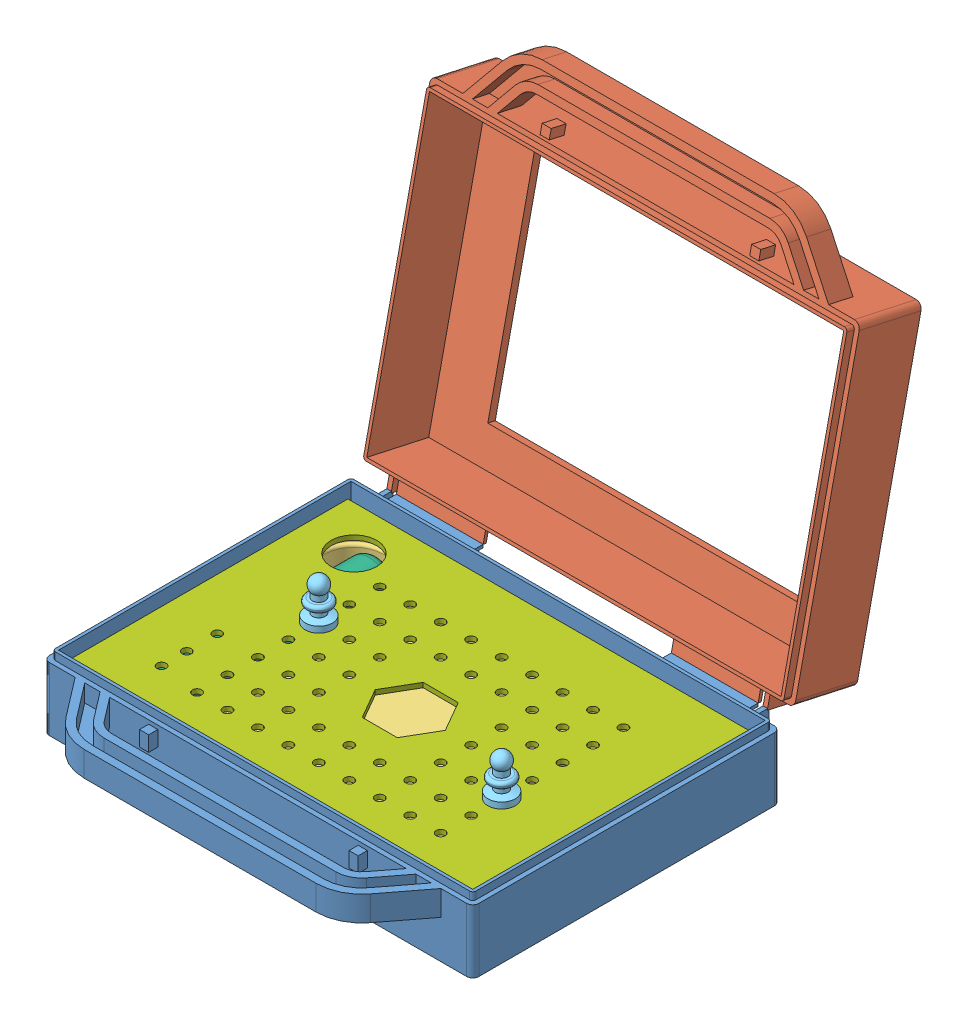
SolidWorks assembly jeu-voyage, configuration Défaut. Lengths in mm.
Overall size (141 142.26 170.67).
8 component instances, 7 part files, 15 mates.
Components (placement in the parent):
- valisette_fond-1: valisette_fond [Défaut] at (-27.5521 -9.989 -62.1133) size (141 23.3 124.3)
- valisette_dessus-1: valisette_dessus [Défaut] at (-27.5521 1.8921 -76.8863) x (-1 0 0) z (0 0.97673 -0.214471) size (141 23.3 124.3)
- support plateau-1: support plateau [Défaut] at (-93.5521 -17.889 36.3867) x (1 0 0) z (0 1 0) size (134 93 15)
- dé-1: dé [Défaut] at (6.4323 -9.889 -21.8934) x (0 1 0) z (0 0 1) size (14 14 14)
- pion-1: pion [Défaut] at (-65.1464 1.9003 -18.5818) x (0.999997 -0.002439 0) z (0 0 1) size (8.97 20.5 8.97)
- sablier(1).eprt-1: sablier(1).eprt [Défaut] at (-76.3521 -9.689 -30.5326) x (0.996399 -0.084784 0) z (0.084784 0.996399 0) size (14.4 80.6 14.4)
- plateau-1: plateau [Défaut] at (-95.2872 -2.889 34.6516) x (1 0 0) z (0 1 0) size (134 93 1.55)
- pion-3: pion [Défaut] at (14.8536 1.9003 1.4182) x (0.999997 -0.002439 0) z (0 0 1) size (8.97 20.5 8.97)
Mates (geometry in assembly coordinates):
- Coïncidente2: coincident: point of valisette_fond-1; point of valisette_dessus-1
- Coïncidente3: coincident: point of valisette_fond-1; point of valisette_dessus-1
- Coïncidente16: coincident aligned: line of valisette_fond-1; line of support plateau-1
- Coïncidente21: coincident aligned: line of valisette_fond-1; line of support plateau-1
- Coïncidente22: coincident anti-aligned: plane of support plateau-1 through (-76.266 -16.889 21.1006) normal (0 1 0); plane of dé-1 through (13.4323 -16.889 -14.8934) normal (0 -1 0)
- Tangent1: tangent anti-aligned: cylinder of sablier(1).eprt-1; plane of support plateau-1 through (-83.5521 -16.889 14.7289) normal (1 0 0)
- Tangent2: tangent anti-aligned: plane of support plateau-1 through (-76.266 -16.889 21.1006) normal (0 1 0); cylinder of sablier(1).eprt-1
- Tangent4: tangent aligned: cylinder of support plateau-1; sphere of sablier(1).eprt-1
- Coïncidente23: coincident anti-aligned: plane of plateau-1 through (-95.2872 -2.889 -58.3484) normal (0 -1 0); plane of support plateau-1 through (-93.5521 -2.889 -56.6133) normal (0 1 0)
- Coïncidente25: coincident aligned: line of support plateau-1; line of plateau-1
- Coïncidente24: coincident aligned: line of support plateau-1; line of plateau-1
- Coaxiale1: concentric aligned: circle of pion-1; circle of plateau-1
- Coïncidente26: coincident aligned: circle of pion-1; plane of plateau-1 through (-95.2872 -1.339 -58.3484) normal (0 1 0)
- Coaxiale2: concentric aligned: circle of plateau-1; circle of ?
- Coïncidente27: coincident aligned: plane of plateau-1 through (-95.2872 -1.339 -58.3484) normal (0 1 0); circle of ?
